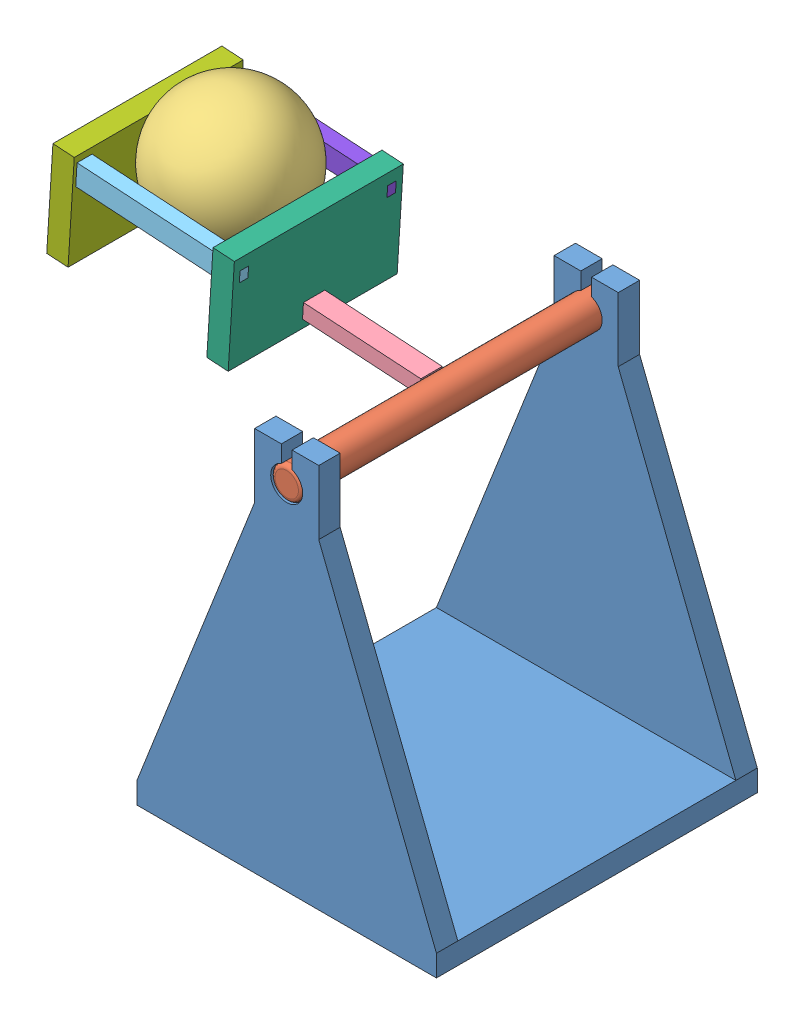
SolidWorks assembly Assembly_Throwing_Arm, configuration Default. Lengths in mm.
Overall size (224.78 249.36 150).
8 component instances, 8 part files, 23 mates.
Components (placement in the parent):
- Base-1: Base [Default] at (-70 150 0) x (0 0 1) z (0 -1 0) size (150 140 180)
- Shaft-1: Shaft [Default] at (-70 165 75) x (-0.062814 -0.998025 0) z (0 0 -1) size (15 127.5 150)
- Ball-1: Ball [Default] at (-171.5955 206.4733 -0.495) x (-0.394061 -0.874008 -0.284299) z (-0.587341 0.001549 0.809338) size (63 63 63)
- Beam-1: Beam [Default] at (-77.4847 165.4785 0.005) x (0 0 -1) z (0.998025 -0.062814 0) size (10 7 140)
- Support_E-1: Support_E [Default] at (-172.8765 202.0402 34.505) x (0 0 -1) z (0.998025 -0.062814 0) size (7 10 85)
- Support_N-1: Support_N [Default] at (-142.6776 164.4575 0.005) x (0 0 -1) z (0.998025 -0.062814 0) size (79 46 10)
- Support_S-1: Support_S [Default] at (-217.5295 169.1685 0.005) x (0 0 -1) z (0.998025 -0.062814 0) size (79 46 10)
- Support_W-1: Support_W [Default] at (-172.8765 202.0402 -34.495) x (0 0 -1) z (0.998025 -0.062814 0) size (7 10 85)
Mates (geometry in assembly coordinates):
- Concentric4: concentric: cylinder of Base-1 through (-70 165 -22.5736) axis (0 0 -1) radius 7.5; cylinder of Shaft-1 through (-70 165 -75) axis (0 0 1) radius 7.5
- Width1: width: plane of Shaft-1 through (-70 165 75) normal (0 0 1); plane of Shaft-1 through (-70 165 -75) normal (0 0 -1); plane of Base-1 through (-70 150 -75) normal (0 0 -1); plane of Base-1 through (0 0 75) normal (0 0 1)
- Parallel7: parallel: plane of Base-1 through (-70 0 0) normal (0 -1 0); plane of assembly through (0 0 0) normal (0 1 0)
- Parallel8: parallel: plane of Base-1 through (0 0 75) normal (0 0 1); plane of assembly through (0 0 0) normal (0 0 1)
- Coincident33: coincident: point of Base-1; point of assembly
- Coincident34: coincident: plane of Shaft-1 through (-62.3728 166.7694 -3.495) normal (0 0 -1); plane of Beam-1 through (-217.3497 172.0244 -3.495) normal (0 0 1)
- Coincident35: coincident: plane of Shaft-1 through (-62.6548 162.2883 3.495) normal (-0.062814 -0.998025 0); plane of Beam-1 through (-217.3497 172.0244 -3.495) normal (0.062814 0.998025 0)
- Tangent1: tangent: cylinder of Shaft-1 through (-70 165 -75) axis (0 0 1) radius 7.5; plane of Beam-1 through (-77.4847 165.4785 0.005) normal (0.998025 -0.062814 0)
- Coincident37: coincident: plane of Beam-1 through (-217.4283 170.7769 5.005) normal (0 0 1); plane of Support_N-1 through (-132.5961 165.4377 5.005) normal (0 0 -1)
- Coincident38: coincident: plane of Beam-1 through (-217.4283 170.7769 -4.995) normal (-0.062814 -0.998025 0); plane of Support_N-1 through (-132.5961 165.4377 -4.995) normal (0.062814 0.998025 0)
- Coincident39: coincident: plane of Beam-1 through (-217.4283 170.7769 5.005) normal (0 0 1); plane of Support_S-1 through (-207.448 170.1488 5.005) normal (0 0 -1)
- Coincident40: coincident: plane of Beam-1 through (-217.4283 170.7769 -4.995) normal (-0.062814 -0.998025 0); plane of Support_S-1 through (-207.448 170.1488 -4.995) normal (0.062814 0.998025 0)
- Coincident41: coincident: plane of Beam-1 through (-217.2083 174.2724 0.005) normal (-0.998025 0.062814 0); plane of Support_S-1 through (-217.5295 169.1685 0.005) normal (-0.998025 0.062814 0)
- Coincident42: coincident: plane of Support_E-1 through (-130.6175 196.8755 36.505) normal (0 0 1); plane of Support_N-1 through (-130.6175 196.8755 36.505) normal (0 0 -1)
- Coincident43: coincident: plane of Support_E-1 through (-130.6175 196.8755 32.505) normal (-0.062814 -0.998025 0); plane of Support_N-1 through (-130.6175 196.8755 32.505) normal (0.062814 0.998025 0)
- Coincident44: coincident: plane of Support_E-1 through (-140.4407 199.9987 34.505) normal (0.998025 -0.062814 0); plane of Support_N-1 through (-142.6776 164.4575 0.005) normal (-0.998025 0.062814 0)
- Coincident45: coincident: plane of Support_E-1 through (-205.3123 204.0816 34.505) normal (-0.998025 0.062814 0); plane of Support_S-1 through (-207.5492 168.5404 0.005) normal (0.998025 -0.062814 0)
- Coincident46: coincident: plane of Support_N-1 through (-130.6175 196.8755 -36.495) normal (0 0 1); plane of Support_W-1 through (-130.6175 196.8755 -36.495) normal (0 0 -1)
- Coincident47: coincident: plane of Support_N-1 through (-130.6175 196.8755 -32.495) normal (0.062814 0.998025 0); plane of Support_W-1 through (-130.6175 196.8755 -36.495) normal (-0.062814 -0.998025 0)
- Coincident48: coincident: plane of Support_S-1 through (-207.5492 168.5404 0.005) normal (0.998025 -0.062814 0); plane of Support_W-1 through (-205.3123 204.0816 -34.495) normal (-0.998025 0.062814 0)
- Tangent2: tangent: sphere of Ball-1; plane of Beam-1 through (-216.9883 177.7679 -4.995) normal (0.062814 0.998025 0)
- Tangent3: tangent: sphere of Ball-1; plane of Support_E-1 through (-140.7548 195.0086 31.005) normal (0 0 -1)
- Tangent4: tangent: sphere of Ball-1; plane of Support_N-1 through (-142.6776 164.4575 0.005) normal (-0.998025 0.062814 0)
